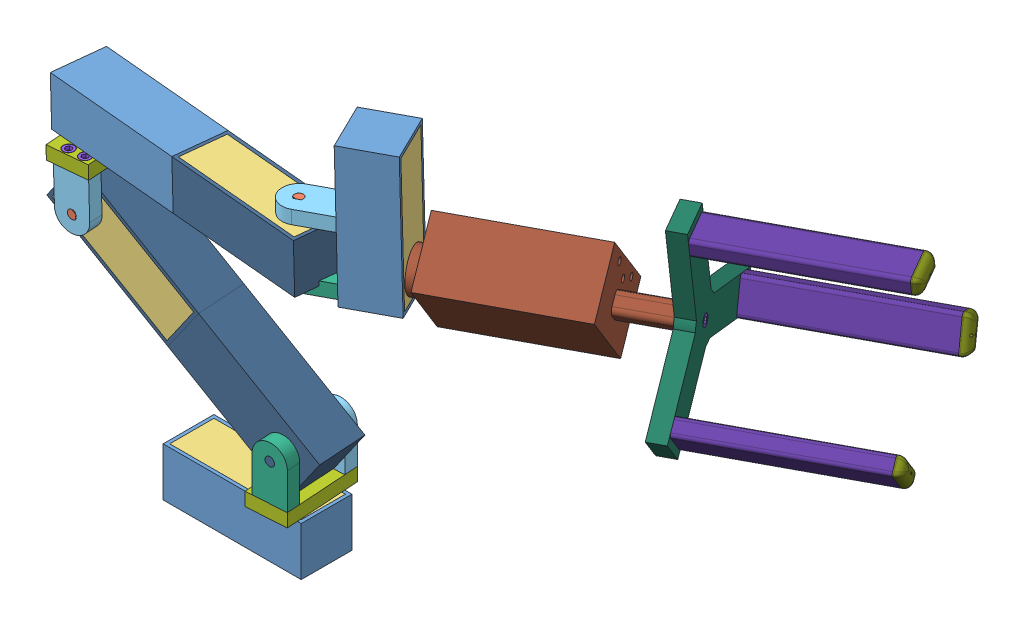
SolidWorks assembly 6DOFArm, configuration Default. Lengths in mm.
Overall size (683.57 461.42 357.47).
82 component instances, 18 part files, 18 mates.
Components (placement in the parent):
- Case1WithBearings-2: Case1WithBearings [Default] at (15.7322 41.1423 -46.3275) size (125 56 46)
  - Motor1WithCase-1: Motor1WithCase [Default] at (-7.1067 -6.2049 -11.0572) size (125 56 46)
    - ArmBase-1: ArmBase [Default] at (40.6555 43.6092 113.8063) size (125 44 46)
    - WormGearMotor-2: WormGearMotor [Default] at (-17.0445 63.1092 113.8063) x (0 0 -1) z (0 -1 0) size (40 117.2 52)
    - ArmBaseCover-2: ArmBaseCover [Default] at (40.6555 87.6092 113.8063) x (-1 0 0) z (0 0 1) size (119 4.5 40)
  - SB608ZZ-1: SB608ZZ [Default] at (73.0487 85.4044 102.7492) x (0 -1 0) z (0 0 1) size (7 22 22)
- ConnectingJoint-2: ConnectingJoint [Default] at (102.3983 127.6243 64.5417) x (-0.997794 0 0.066385) z (-0.066385 0 -0.997794) size (36 60 68.86)
  - BearingJoints-1: BearingJoints [Default] at (10.0484 39.9223 31.0061) size (30 48 12)
  - BearingJoints2-1: BearingJoints2 [Default] at (10.0484 39.9223 -12.9939) x (-1 0 0) z (0 0 -1) size (30 48 12)
  - JointBottom-1: JointBottom [Default] at (13.0484 -5.0777 9.0061) x (0 0 -1) z (1 0 0) size (68 12 36)
  - socket head cap screw_iso-1: socket head cap screw_iso [ISO 4762 M6 x 20 - 20S] at (3.0484 -5.0777 -18.9939) x (0 1 0) z (-0.488199 0 0.872732) size (26 10 10)
  - socket head cap screw_iso-2: socket head cap screw_iso [ISO 4762 M6 x 20 - 20S] at (3.0484 -5.0777 37.0061) x (0 1 0) z (0 0 1) size (26 10 10)
  - socket head cap screw_iso-3: socket head cap screw_iso [ISO 4762 M6 x 20 - 20S] at (17.0484 -5.0777 37.0061) x (0 1 0) z (0 0 1) size (26 10 10)
  - socket head cap screw_iso-4: socket head cap screw_iso [ISO 4762 M6 x 20 - 20S] at (17.0484 -5.0777 -18.9939) x (0 1 0) z (-0.513591 0 0.858035) size (26 10 10)
  - M5X10-1: M5X10 [Default] at (22.2578 2.0842 9.2195) x (-1 0 0) z (0 -0.924225 -0.381849) size (15 8.5 8.5)
- Motor2WithCase-1: Motor2WithCase [Default] at (-91.6932 127.4425 72.641) x (0.699795 -0.562759 -0.439987) z (0.690752 0.376107 0.617581) size (139.16 102.77 112.77)
  - WormGearMotor-2: WormGearMotor [Default] at (22.8097 94.5076 102.0809) x (0.052143 -0.73415 -0.676982) z (-0.392561 -0.6384 0.662074) size (40 117.2 52)
  - ArmBaseCover-2: ArmBaseCover [Default] at (85.4103 96.8062 104.4099) x (-0.918247 0.231235 -0.321487) z (-0.052143 0.73415 0.676982) size (119 4.5 40)
  - ArmBase2-1: ArmBase2 [Default] at (68.1376 68.7166 133.5411) x (0.918247 -0.231235 0.321487) z (-0.052143 0.73415 0.676982) size (125 56 46)
- Motor2WithCase-2: Motor2WithCase [Default] at (-47.6538 96.7522 61.2867) x (-0.758696 0.476789 0.443906) z (0.073969 0.740062 -0.668459) size (139.16 102.77 112.77)
  - WormGearMotor-2: WormGearMotor [Default] at (22.8097 94.5076 102.0809) x (0.052143 -0.73415 -0.676982) z (-0.392561 -0.6384 0.662074) size (40 117.2 52)
  - ArmBaseCover-2: ArmBaseCover [Default] at (85.4103 96.8062 104.4099) x (-0.918247 0.231235 -0.321487) z (-0.052143 0.73415 0.676982) size (119 4.5 40)
  - ArmBase2-1: ArmBase2 [Default] at (68.1376 68.7166 133.5411) x (0.918247 -0.231235 0.321487) z (-0.052143 0.73415 0.676982) size (125 56 46)
- ConnectingJoint-3: ConnectingJoint [Default] at (-67.6434 323.1923 57.8028) x (-0.997453 -0.026156 0.066362) z (0.066385 0 0.997794) size (36 60 68.86)
  - BearingJoints-1: BearingJoints [Default] at (10.0484 39.9223 31.0061) size (30 48 12)
  - BearingJoints2-1: BearingJoints2 [Default] at (10.0484 39.9223 -12.9939) x (-1 0 0) z (0 0 -1) size (30 48 12)
  - JointBottom-1: JointBottom [Default] at (13.0484 -5.0777 9.0061) x (0 0 -1) z (1 0 0) size (68 12 36)
  - socket head cap screw_iso-1: socket head cap screw_iso [ISO 4762 M6 x 20 - 20S] at (3.0484 -5.0777 -18.9939) x (0 1 0) z (-0.488199 0 0.872732) size (26 10 10)
  - socket head cap screw_iso-2: socket head cap screw_iso [ISO 4762 M6 x 20 - 20S] at (3.0484 -5.0777 37.0061) x (0 1 0) z (0 0 1) size (26 10 10)
  - socket head cap screw_iso-3: socket head cap screw_iso [ISO 4762 M6 x 20 - 20S] at (17.0484 -5.0777 37.0061) x (0 1 0) z (0 0 1) size (26 10 10)
  - socket head cap screw_iso-4: socket head cap screw_iso [ISO 4762 M6 x 20 - 20S] at (17.0484 -5.0777 -18.9939) x (0 1 0) z (-0.513591 0 0.858035) size (26 10 10)
  - M5X10-1: M5X10 [Default] at (22.2578 2.0842 9.2195) x (-1 0 0) z (0 -0.924225 -0.381849) size (15 8.5 8.5)
- Case1WithBearings-3: Case1WithBearings [Default] at (1.8394 411.6636 -26.0327) x (-0.993263 -0.025735 -0.112984) z (-0.112901 -0.004673 0.993595) size (125 56 46)
  - Motor1WithCase-1: Motor1WithCase [Default] at (-7.1067 -6.2049 -11.0572) size (125 56 46)
    - ArmBase-1: ArmBase [Default] at (40.6555 43.6092 113.8063) size (125 44 46)
    - WormGearMotor-2: WormGearMotor [Default] at (-17.0445 63.1092 113.8063) x (0 0 -1) z (0 -1 0) size (40 117.2 52)
    - ArmBaseCover-2: ArmBaseCover [Default] at (40.6555 87.6092 113.8063) x (-1 0 0) z (0 0 1) size (119 4.5 40)
  - SB608ZZ-1: SB608ZZ [Default] at (73.0487 85.4044 102.7492) x (0 -1 0) z (0 0 1) size (7 22 22)
- Case2WithBearings-1: Case2WithBearings [Default] at (39.0277 211.0181 -149.9358) x (0.959902 0.114038 0.256092) z (-0.239552 -0.140825 0.960616) size (134.86 85.12 69.25)
  - Motor2WithCase-1: Motor2WithCase [Default] at (13.0916 77.6526 105.2229) size (139.16 102.77 112.77) (flexible)
    - WormGearMotor-2: WormGearMotor [Default] at (48.4991 85.9575 99.1046) x (-0.145545 -0.119013 -0.982167) z (-0.089391 -0.987096 0.132857) size (40 117.2 52)
    - ArmBaseCover-2: ArmBaseCover [Default] at (107.5413 103.9597 88.1739) x (-0.985305 0.107134 0.133028) z (0.145545 0.119013 0.982167) size (119 4.5 40)
    - ArmBase2-1: ArmBase2 [Default] at (103.6081 60.5275 94.0196) x (0.985305 -0.107134 -0.133028) z (0.145545 0.119013 0.982167) size (125 56 46)
  - SB608ZZ-1: SB608ZZ [Default] at (159.91 181.3289 187.6107) x (-0.089391 -0.987096 0.132857) z (0.812185 -0.149453 -0.563932) size (7 22 22)
  - SB608ZZ-2: SB608ZZ [Default] at (155.8874 136.9096 193.5893) x (-0.089391 -0.987096 0.132857) z (0.005977 0.132857 0.991117) size (7 22 22)
- WristJoint-1: WristJoint [Default] at (245.6568 249.506 63.906) x (-0.443258 -0.010015 -0.896338) z (-0.026098 0.999658 0.001736) size (46 104 125)
  - ConnectingJoint2-1: ConnectingJoint2 [Default] at (19.8862 87.6652 94.835) size (46 92 125)
    - BearingJoints-1: BearingJoints [Default] at (9.8682 32.6089 36.0698) size (30 48 12)
    - BearingJoints2-1: BearingJoints2 [Default] at (9.8682 32.6089 -3.9302) x (-1 0 0) z (0 0 -1) size (30 48 12)
    - ArmBase-1: ArmBase [Default] at (9.8682 -0.3911 46.5698) x (0 0 -1) z (-1 0 0) size (125 44 46)
  - WormGearMotor-1: WormGearMotor [Default] at (29.7544 67.7741 199.1048) x (1 0 0) z (0 1 0) size (40 117.2 52)
  - ArmBaseCover-1: ArmBaseCover [Default] at (29.7544 43.2741 141.4048) x (0 0 1) z (-1 0 0) size (119 4.5 40)
  - SB608ZZ-1: SB608ZZ [Default] at (29.7544 120.2741 86.9048) x (0 0 1) z (-1 0 0) size (7 22 22)
  - SB608ZZ-2: SB608ZZ [Default] at (29.7544 120.2741 127.9048) x (0 0 1) z (-0.001374 0.999999 0) size (7 22 22)
  - SB608ZZ-3: SB608ZZ [Default] at (29.7544 39.2741 101.9048) x (0 1 0) z (0 0 1) size (7 22 22)
- GrapperWithServos-2: GrapperWithServos [Default] at (336.0552 295.3636 27.6865) x (0.264305 0.773327 0.576288) z (-0.896014 -0.024163 0.443367) size (170.88 147.99 355)
  - ServoHolder-1: ServoHolder [Default] at (20.6091 41.5283 66.4389) size (76 55.75 187)
  - ServoWithHornCover-1: ServoWithHornCover [Default] at (-47.2507 32.9202 59.0729) x (0 0 -1) z (1 0 0) size (60.01 49.75 41.52) (flexible)
    - MG996R-1: MG996R [Default] at (22.884 11.6081 50.6098) size (53.5 42.75 19.5)
    - ServoHornWithGroove-1: ServoHornWithGroove [Default] at (12.384 56.3581 50.6098) x (0.653288 0 0.75711) z (0.75711 0 -0.653288) size (30 9.5 30)
    - ServoCover-1: ServoCover [Default] at (34.0772 41.3581 67.8598) x (-1 0 0) z (0 0 -1) size (57.5 20 34.5)
  - ServoWithHornCover-2: ServoWithHornCover [Default] at (-12.7507 32.9202 59.0729) x (0 0 -1) z (1 0 0) size (60.01 49.75 41.52) (flexible)
    - MG996R-1: MG996R [Default] at (22.884 11.6081 50.6098) size (53.5 42.75 19.5)
    - ServoHornWithGroove-1: ServoHornWithGroove [Default] at (12.384 56.3581 50.6098) x (0.586538 0 0.809922) z (0.809922 0 -0.586538) size (30 9.5 30)
    - ServoCover-1: ServoCover [Default] at (34.0772 41.3581 67.8598) x (-1 0 0) z (0 0 -1) size (57.5 20 34.5)
  - 3GripperAssembly-1: 3GripperAssembly [Default] at (-30.3334 -49.3942 19.9719) x (1 0 0) z (0 1 0) size (170.88 173 147.99)
    - EndEffector3Grapper-1: EndEffector3Grapper [Default] at (50.9425 60.533 115.9226) size (170.88 20 147.99)
    - FingerAssembly-1: FingerAssembly [Default] at (105.0348 198.5242 138.6511) x (-0.5 0 0.866025) z (0 1 0) size (30 15 158)
      - FingerTip-1: FingerTip [Default] at (7.3627 17.1904 24.0088) size (30 15 11)
      - Finger-1: Finger [Default] at (7.3627 18.2904 -122.9912) x (1 0 0) z (0 -1 0) size (30 150 15)
    - FingerAssembly-2: FingerAssembly [Default] at (4.2129 198.5242 151.4036) x (-0.5 0 -0.866025) z (0 1 0) size (30 15 158)
      - FingerTip-1: FingerTip [Default] at (7.3627 17.1904 24.0088) size (30 15 11)
      - Finger-1: Finger [Default] at (7.3627 18.2904 -122.9912) x (1 0 0) z (0 -1 0) size (30 150 15)
    - FingerAssembly-3: FingerAssembly [Default] at (43.5799 198.5242 57.713) x (1 0 0) z (0 1 0) size (30 15 158)
      - FingerTip-1: FingerTip [Default] at (7.3627 17.1904 24.0088) size (30 15 11)
      - Finger-1: Finger [Default] at (7.3627 18.2904 -122.9912) x (1 0 0) z (0 -1 0) size (30 150 15)
  - ServoWithHornCover-4: ServoWithHornCover [Default] at (-30.0007 32.9202 119.5729) x (0 0 -1) z (1 0 0) size (60.01 49.75 41.52)
    - MG996R-1: MG996R [Default] at (22.884 11.6081 50.6098) size (53.5 42.75 19.5)
    - ServoHornWithGroove-1: ServoHornWithGroove [Default] at (12.384 56.3581 50.6098) x (-0.837169 0 -0.546944) z (-0.546944 0 0.837169) size (30 9.5 30)
    - ServoCover-1: ServoCover [Default] at (34.0772 41.3581 67.8598) x (-1 0 0) z (0 0 -1) size (57.5 20 34.5)
  - ServoHolderCover-1: ServoHolderCover [Default] at (20.6091 94.2783 66.4389) x (0 0 -1) z (1 0 0) size (118 3 70)
  - socket head cap screw_iso-1: socket head cap screw_iso [ISO 4762 M6 x 20 - 20S] at (20.6091 66.5283 -55.5611) x (0 0 1) z (-0.923728 -0.383049 0) size (26 10 10)
Mates (geometry in assembly coordinates):
- Concentric4: concentric aligned: cylinder of Case1WithBearings-2/SB608ZZ-1 through (88.7809 119.8466 56.4217) axis (0 -1 0) radius 11; cylinder of ConnectingJoint-2/JointBottom-1 through (88.7809 126.5466 56.4217) axis (0 -1 0) radius 11
- Coincident4: coincident anti-aligned: plane of Case1WithBearings-2/SB608ZZ-1 through (99.4809 126.5466 56.4217) normal (0 1 0); plane of ConnectingJoint-2/JointBottom-1 through (88.7809 126.5466 56.4217) normal (0 -1 0)
- Concentric5: concentric anti-aligned: cylinder of ConnectingJoint-2/BearingJoints-1 through (90.0483 167.5466 30.2799) axis (0.066385 0 0.997794) radius 11; cylinder of Motor2WithCase-1/WormGearMotor-2 through (90.8449 167.5466 42.2534) axis (-0.066385 0 -0.997794) radius 4
- Coincident5: coincident anti-aligned: plane of ConnectingJoint-2/BearingJoints-1 through (90.3138 167.5466 34.2711) normal (0.066385 0 0.997794); plane of Motor2WithCase-1/ArmBaseCover-2 through (57.823 189.9056 36.4327) normal (-0.066385 0 -0.997794)
- Coincident6: coincident aligned: plane of Motor2WithCase-1/ArmBase2-1 through (19.4039 244.2443 38.9888) normal (0.564802 0.824371 -0.037577); plane of Motor2WithCase-2/ArmBase2-1 through (22.3248 244.2443 82.8917) normal (0.564802 0.824371 -0.037577)
- Coincident7: coincident aligned: plane of Motor2WithCase-1/ArmBaseCover-2 through (57.823 189.9056 36.4327) normal (-0.066385 0 -0.997794); plane of Motor2WithCase-2/ArmBase2-1 through (-44.996 260.6619 43.2734) normal (-0.066385 0 -0.997794)
- Coincident8: coincident anti-aligned: plane of Motor2WithCase-1/ArmBase2-1 through (19.4039 244.2443 38.9888) normal (-0.822552 0.56605 0.054725); plane of Motor2WithCase-2/ArmBase2-1 through (22.3248 244.2443 82.8917) normal (0.822552 -0.56605 -0.054725)
- Concentric6: concentric anti-aligned: cylinder of Motor2WithCase-2/WormGearMotor-2 through (-75.097 283.0209 81.3556) axis (0.066385 0 0.997794) radius 4; cylinder of ConnectingJoint-3/BearingJoints-1 through (-74.3004 283.0209 93.3292) axis (-0.066385 0 -0.997794) radius 11
- Coincident9: coincident anti-aligned: plane of Motor2WithCase-2/ArmBase2-1 through (-44.996 260.6619 43.2734) normal (-0.066385 0 -0.997794); plane of ConnectingJoint-3/BearingJoints2-1 through (-77.4868 283.0209 45.4351) normal (0.066385 0 0.997794)
- Concentric7: concentric aligned: cylinder of ConnectingJoint-3/JointBottom-1 through (-80.0888 323.9284 67.6568) axis (-0.026098 0.999658 0.001736) radius 11; cylinder of Case1WithBearings-3/SB608ZZ-1 through (-80.2636 330.6261 67.6684) axis (-0.026098 0.999658 0.001736) radius 11
- Coincident10: coincident anti-aligned: plane of ConnectingJoint-3/JointBottom-1 through (-80.1932 327.927 67.6637) normal (-0.026098 0.999658 0.001736); plane of Case1WithBearings-3/Motor1WithCase-1/ArmBase-1 through (-40.9593 328.9435 72.1266) normal (0.026098 -0.999658 -0.001736)
- Coincident11: coincident anti-aligned: plane of Case1WithBearings-3/Motor1WithCase-1/ArmBase-1 through (18.523 330.4445 102.0408) normal (0.993263 0.025735 0.112984); plane of Case2WithBearings-1/Motor2WithCase-1/ArmBase2-1 through (17.3746 374.4295 102.1172) normal (-0.993263 -0.025735 -0.112984)
- Coincident12: coincident aligned: plane of Case1WithBearings-3/Motor1WithCase-1/ArmBase-1 through (18.523 330.4445 102.0408) normal (-0.112901 -0.004673 0.993595); plane of Case2WithBearings-1/Motor2WithCase-1/ArmBase2-1 through (17.3746 374.4295 102.1172) normal (-0.112901 -0.004673 0.993595)
- Coincident13: coincident aligned: plane of Case1WithBearings-3/Motor1WithCase-1/ArmBase-1 through (-42.1076 372.9285 72.203) normal (-0.026098 0.999658 0.001736); plane of Case2WithBearings-1/Motor2WithCase-1/ArmBaseCover-2 through (82.0503 376.1454 86.326) normal (-0.026098 0.999658 0.001736)
- Concentric8: concentric aligned: cylinder of Case2WithBearings-1/SB608ZZ-1 through (121.3547 374.4629 90.7842) axis (0.026098 -0.999658 -0.001736) radius 11; cylinder of WristJoint-1/ConnectingJoint2-1/BearingJoints-1 through (121.1798 381.1606 90.7958) axis (0.026098 -0.999658 -0.001736) radius 15
- Coincident14: coincident anti-aligned: plane of Case2WithBearings-1/SB608ZZ-1 through (117.4373 381.0803 80.772) normal (-0.026098 0.999658 0.001736); plane of WristJoint-1/ConnectingJoint2-1/BearingJoints-1 through (121.1798 381.1606 90.7958) normal (0.026098 -0.999658 -0.001736)
- Coincident15: coincident anti-aligned: plane of WristJoint-1/SB608ZZ-3 through (199.3611 350.2362 64.4166) normal (0.896014 0.024163 -0.443367); plane of GrapperWithServos-2/ServoHolder-1 through (194.6183 350.129 54.8258) normal (-0.896014 -0.024163 0.443367)
- Concentric9: concentric aligned: cylinder of WristJoint-1/SB608ZZ-3 through (188.615 349.9672 57.7963) axis (-0.896014 -0.024163 0.443367) radius 11; cylinder of GrapperWithServos-2/ServoHolder-1 through (194.6183 350.129 54.8258) axis (-0.896014 -0.024163 0.443367) radius 11
